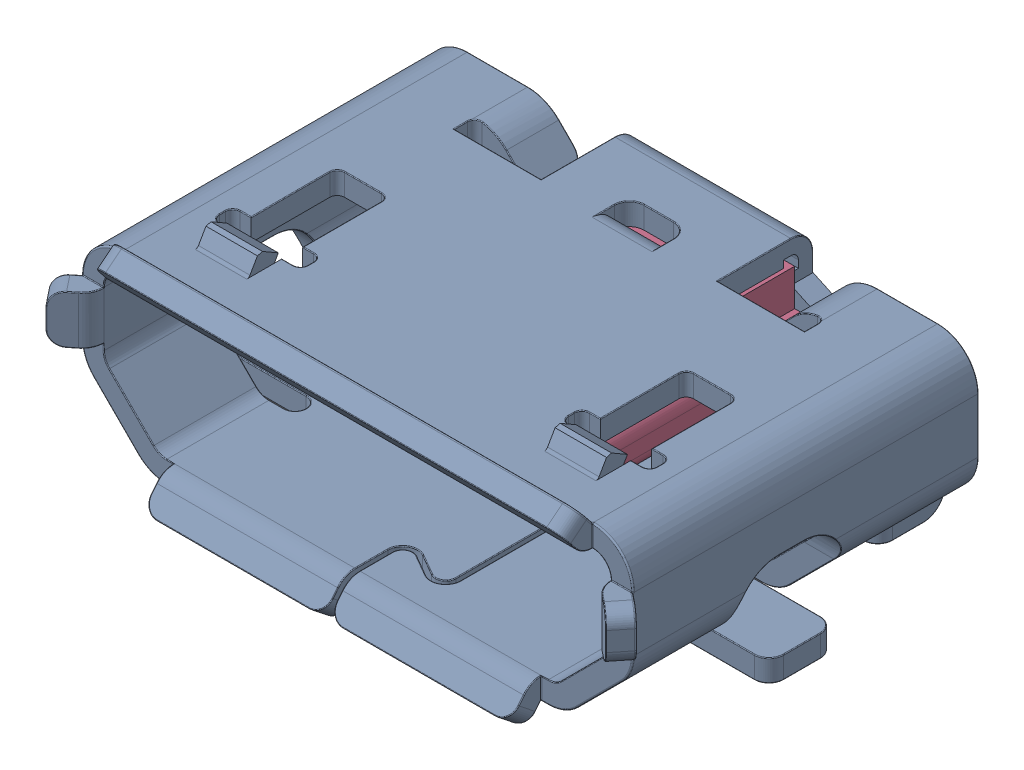
SolidWorks assembly raspberry_pi__micro_USB, configuration Default. Lengths in mm.
Overall size (7.99 2.94 5.43).
2 component instances, 2 part files, 0 mates.
Components (placement in the parent):
- raspberry_pi__micro_USB_cover-1: raspberry_pi__micro_USB_cover [Default] at (-14.4796 6.4719 -16.0085) size (7.99 2.94 5.43)
- raspberry_pi__micro_USB_contacts-1: raspberry_pi__micro_USB_contacts [Default] at (-14.4796 6.4719 -20.7085) size (6.9 2.16 4.2)
